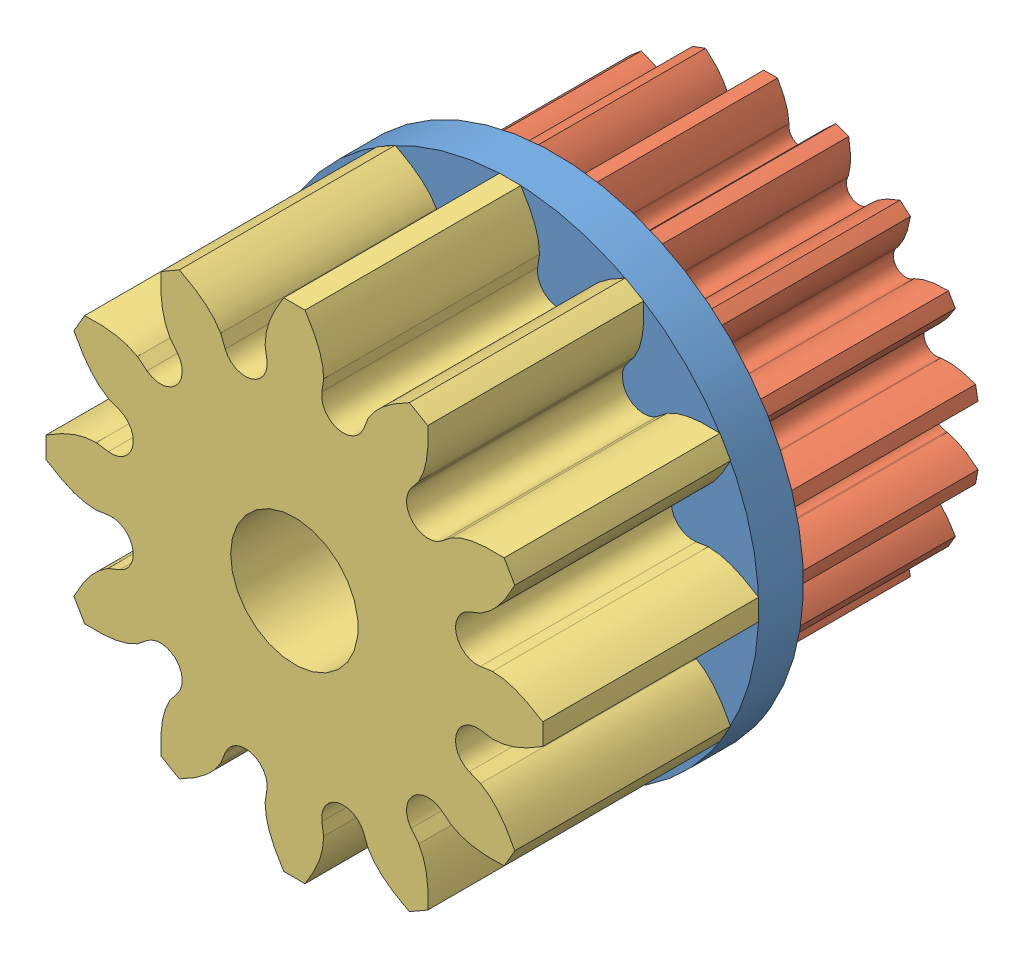
SolidWorks assembly OrangeSunGear, configuration Default. Lengths in mm.
Overall size (9.6 9.6 6.64).
3 component instances, 3 part files, 8 mates.
Components (placement in the parent):
- OrangeIntermediaryPlate-1: OrangeIntermediaryPlate [Default] at (0 0 3.0099) x (0.83755 -0.546361 0) z (0 0 1)
- OrangeSpurSmall-2: OrangeSpurSmall [Default] at origin
- OrangeSpurLarge-2: OrangeSpurLarge [Default] at (0 0 3.6322)
Mates (geometry in assembly coordinates):
- Concentric3: concentric: cylinder of OrangeIntermediaryPlate-1 through (0 0 3.6322) axis (0 0 -1) radius 0.889; cylinder of OrangeSpurSmall-2 through (0 0 3.0099) axis (0 0 -1) radius 0.889
- Concentric4: concentric: cylinder of OrangeIntermediaryPlate-1 through (0 0 3.6322) axis (0 0 -1) radius 0.889; cylinder of OrangeSpurLarge-2 through (0 0 6.6421) axis (0 0 -1) radius 0.889
- Coincident3: coincident: plane of OrangeIntermediaryPlate-1 through (0 0 3.6322) normal (0 0 1); plane of OrangeSpurLarge-2 through (0 0 3.6322) normal (0 0 -1)
- Coincident4: coincident: plane of OrangeIntermediaryPlate-1 through (0 0 3.0099) normal (0 0 -1); plane of OrangeSpurSmall-2 through (0 0 3.0099) normal (0 0 1)
- Coincident6: coincident: plane of OrangeSpurSmall-2 through (0 0 0) normal (1 0 0); plane of assembly through (0 0 0) normal (1 0 0)
- Coincident7: coincident: plane of OrangeSpurSmall-2 through (0 0 0) normal (0 0 1); plane of assembly through (0 0 0) normal (0 0 1)
- Coincident8: coincident: plane of OrangeSpurSmall-2 through (0 0 0) normal (0 1 0); plane of assembly through (0 0 0) normal (0 1 0)
- Coincident9: coincident: plane of OrangeSpurLarge-2 through (0 0 3.6322) normal (0 1 0); plane of assembly through (0 0 0) normal (0 1 0)
